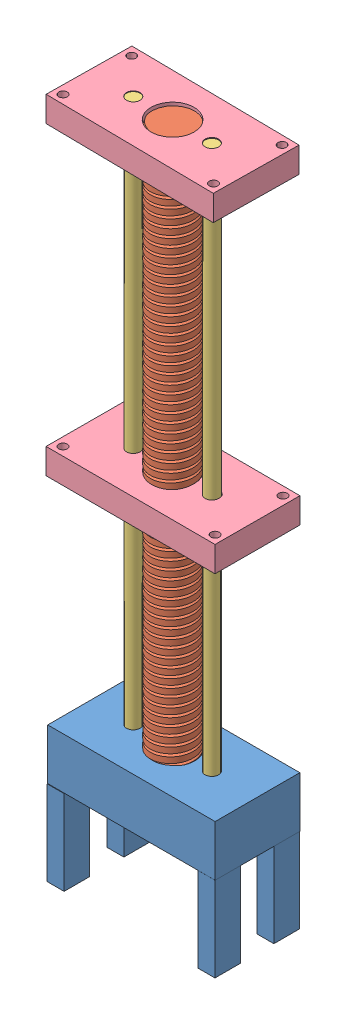
SolidWorks assembly Ensamblaje bueno cx, configuration Predeterminado. Lengths in mm.
Overall size (100.66 401.07 51.29).
6 component instances, 4 part files, 6 mates.
Components (placement in the parent):
- base eee-1: base eee [Predeterminado] at (-0.8152 27.3003 94.9143) x (1 0 0) z (0 -1 0) size (98.88 50.29 80)
- Esparrago 35 cm-1: Esparrago 35 cm [Predeterminado] at (2.9773 346.9252 98.1052) x (0.735608 0 -0.677407) z (0 -1 0) size (26.06 26.33 351.78)
- 355-1: 355 [Predeterminado] at (-20.6483 348.0158 97.3894) x (0.992373 0 -0.123274) z (0 -1 0) size (8 8 350)
- 355-2: 355 [Predeterminado] at (26.3378 347.8825 97.9987) x (0.990833 0 -0.13509) z (0 -1 0) size (8 8 350)
- Pieza1-1: Pieza1 [Predeterminado] at (19.6873 168.6036 73.3275) x (0.999996 0 0.002655) z (0 -1 0) size (100 50 15)
- Pieza1-2: Pieza1 [Predeterminado] at (19.9423 348.3656 73.7464) x (0.999916 0 0.012986) z (0 -1 0) size (100 50 15)
Mates (geometry in assembly coordinates):
- Concéntrica6: concentric: circle of assembly; cylinder of assembly; circle of base eee-1; cylinder of Esparrago 35 cm-1 through (3.3914 -3.0748 98.8306) axis (0 1 0) radius 12.7
- Concéntrica9: concentric: circle of assembly; cylinder of assembly; circle of base eee-1; cylinder of 355-1 through (-20.7333 -1.9842 98.2203) axis (0 1 0) radius 4
- Concéntrica10: concentric: circle of assembly; cylinder of assembly; circle of base eee-1; cylinder of 355-2 through (26.2627 -2.1175 98.8306) axis (0 1 0) radius 4
- Coincidente2: coincident: cylinder of assembly; circle of assembly; cylinder of 355-1 through (-20.7333 -1.9842 98.2203) axis (0 1 0) radius 4; circle of Pieza1-1
- Coincidente4: coincident: cylinder of assembly; circle of assembly; cylinder of 355-1 through (-20.7333 -1.9842 98.2203) axis (0 1 0) radius 4; circle of Pieza1-2
- Coincidente5: coincident: cylinder of assembly; circle of assembly; cylinder of 355-2 through (26.2627 -2.1175 98.8306) axis (0 1 0) radius 4; circle of Pieza1-2
